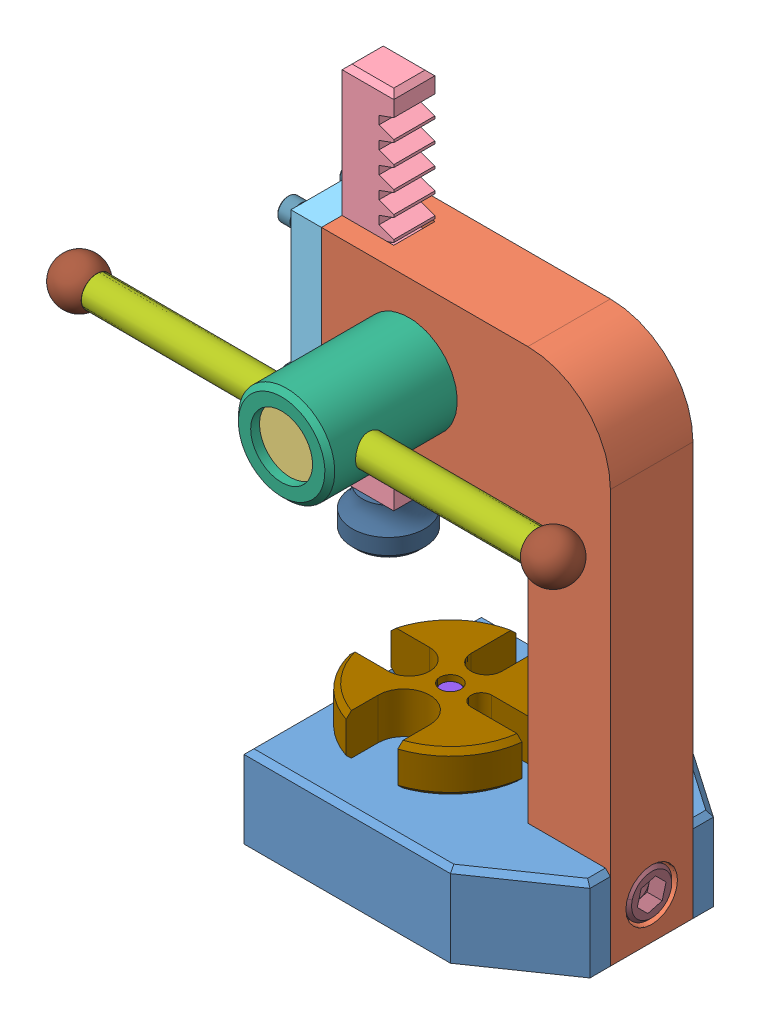
SolidWorks assembly Arbor_Press, configuration Default. Lengths in mm.
Overall size (160.09 192.74 88.38).
18 component instances, 14 part files, 29 mates.
Components (placement in the parent):
- Base-2: Base [Default] at origin size (88.9 25.4 73.03)
- Column Detail-1: Column Detail [Default] at (88.9 -12.7 0) size (88.9 152.4 25.4)
- Gear-1: Gear [Default] at (26.924 114.3 49.1998) x (0 0 -1) z (0.999994 -0.00338 0) size (61.9 29.01 29.01)
- Rack Gear-1: Rack Gear [Default] at (7.9375 68.9149 0) x (0 1 0) z (0 0 -1) size (111.12 15.88 12.65)
- Cover Plate-1: Cover Plate [Default] at (-9.398 114.3 0) x (0 0 1) z (1 0 0) size (25.4 50.8 9.4)
- Sleeve-1: Sleeve [Default] at (26.924 114.3 51.8668) x (0 0 -1) z (0.999994 -0.00338 0) size (42.62 29.64 29.64)
- Handle-1: Handle [Default] at (24.8888 114.3069 39.1668) x (0.999994 -0.00338 0) z (0.001333 0.394498 0.918896) size (152.4 9.45 9.45)
- Table Pin-1: Table Pin [Default] at (26.9748 -1.5748 0) x (-0.301577 0 0.953442) z (0 1 0) size (6.48 6.48 25.4)
- Table-1: Table [Default] at (26.9748 12.7 0) size (49.79 12.7 49.08)
- Rack Pad-1: Rack Pad [Default] at (7.9375 56.2149 0) size (22.24 26.97 22.24)
- Ball End-1: Ball End [Default] at (-47.9909 114.5532 39.1668) x (0.999994 -0.00338 0) z (0 0 1) size (12.45 14.27 14.27)
- Ball End-2: Ball End [Default] at (97.7685 114.0606 39.1668) x (-0.999994 0.00338 0) z (-0.002583 -0.764273 0.644888) size (12.45 14.27 14.27)
- Screw-1: Screw [Default] at (26.924 114.3 -3.2004) x (0.149888 -0.988703 0) z (0.988703 0.149888 0) size (19.05 14.74 19.05)
- _375-16x1_25x1_25-c_shcsa-1: _375-16x1_25x1_25-c_shcsa [Default] at (88.9 0 0) x (-1 0 0) z (0 0.259964 0.965618) size (41.27 14.29 14.29)
- 8-32 Socket Head Cap Screw_AI-2: 8-32 Socket Head Cap Screw_AI [PreviewCfg] at (-13.5636 136.525 -9.525) size (23.22 6.86 6.86)
- 8-32 Socket Head Cap Screw_AI-5: 8-32 Socket Head Cap Screw_AI [PreviewCfg] at (-13.5636 136.525 9.525) size (23.22 6.86 6.86)
- 8-32 Socket Head Cap Screw_AI-6: 8-32 Socket Head Cap Screw_AI [PreviewCfg] at (-13.5636 92.075 -9.525) size (23.22 6.86 6.86)
- 8-32 Socket Head Cap Screw_AI-7: 8-32 Socket Head Cap Screw_AI [PreviewCfg] at (-13.5636 92.075 9.525) size (23.22 6.86 6.86)
Mates (geometry in assembly coordinates):
- Concentric1: concentric: cylinder of Base-2 through (63.5 0 0) axis (1 0 0) radius 3.9688; cylinder of Column Detail-1 through (88.9 0 0) axis (1 0 0) radius 5.0419
- Coincident1: coincident: plane of Base-2 through (63.5 -12.7 -12.7) normal (1 0 0); plane of Column Detail-1 through (63.5 79.248 12.7) normal (-1 0 0)
- Parallel1: parallel: plane of Base-2 through (0 12.7 36.5125) normal (0 0 1); plane of Column Detail-1 through (63.5 114.3 12.7) normal (0 0 1)
- Concentric3: concentric: cylinder of Column Detail-1 through (26.924 114.3 12.7) axis (0 0 1) radius 6.35; cylinder of Gear-1 through (26.924 114.3 49.1998) axis (0 0 -1) radius 6.3348
- Coincident3: coincident: plane of Column Detail-1 through (63.5 114.3 -12.7) normal (0 0 -1); plane of Gear-1 through (26.9454 120.6347 -12.7) normal (0 0 -1)
- Width1: width: plane of Column Detail-1 through (15.9004 -12.7 -6.35) normal (0 0 1); plane of Column Detail-1 through (15.9004 -12.7 6.35) normal (0 0 -1); plane of Rack Gear-1 through (15.875 180.0399 -6.3246) normal (0 0 -1); plane of Rack Gear-1 through (15.875 180.0399 6.3246) normal (0 0 1)
- Coincident5: coincident: plane of Column Detail-1 through (0 139.7 12.7) normal (-1 0 0); plane of Rack Gear-1 through (0 180.0399 -6.3246) normal (-1 0 0)
- Concentric5: concentric: cylinder of Column Detail-1 through (0 136.525 -9.525) axis (-1 0 0) radius 1.7272; cylinder of Cover Plate-1 through (0 136.525 -9.525) axis (1 0 0) radius 2.2479
- Concentric6: concentric: cylinder of Column Detail-1 through (0 92.075 -9.525) axis (-1 0 0) radius 1.7272; cylinder of Cover Plate-1 through (0 92.075 -9.525) axis (1 0 0) radius 2.2479
- Coincident6: coincident: plane of Column Detail-1 through (0 139.7 12.7) normal (-1 0 0); plane of Cover Plate-1 through (0 114.3 0) normal (1 0 0)
- Concentric7: concentric: cylinder of Gear-1 through (26.924 114.3 49.1998) axis (0 0 -1) radius 9.4932; cylinder of Sleeve-1 through (26.924 114.3 9.2456) axis (0 0 -1) radius 9.525
- Concentric8: concentric: cylinder of Gear-1 through (36.4172 114.2679 39.1668) axis (0.999994 -0.00338 0) radius 4.7625; cylinder of Sleeve-1 through (41.7448 114.2499 39.1668) axis (0.999994 -0.00338 0) radius 4.7625
- Concentric9: concentric: cylinder of Gear-1 through (36.4172 114.2679 39.1668) axis (0.999994 -0.00338 0) radius 4.7625; cylinder of Handle-1 through (-51.3108 114.5644 39.1668) axis (-0.999994 0.00338 0) radius 4.7244
- Concentric10: concentric: cylinder of Base-2 through (26.9748 12.7 0) axis (0 1 0) radius 3.2385; cylinder of Table Pin-1 through (26.9748 23.8252 0) axis (0 -1 0) radius 3.2385
- Coincident7: coincident: plane of Base-2 through (26.9748 -1.5748 0) normal (0 1 0); plane of Table Pin-1 through (26.9748 -1.5748 0) normal (0 -1 0)
- Concentric11: concentric: cylinder of Table Pin-1 through (26.9748 23.8252 0) axis (0 -1 0) radius 3.2385; cylinder of Table-1 through (26.9748 25.4 0) axis (0 1 0) radius 3.2385
- Coincident8: coincident: plane of Base-2 through (0 12.7 0) normal (0 1 0); plane of Table-1 through (26.9748 12.7 0) normal (0 -1 0)
- Concentric12: concentric: cylinder of Rack Gear-1 through (7.9375 68.9149 0) axis (0 -1 0) radius 3.175; cylinder of Rack Pad-1 through (7.9375 56.2149 0) axis (0 1 0) radius 3.1686
- Coincident9: coincident: plane of Rack Gear-1 through (7.9375 68.9149 0) normal (0 -1 0); plane of Rack Pad-1 through (15.875 68.9149 0) normal (0 1 0)
- Concentric13: concentric: cylinder of Handle-1 through (-51.3108 114.5644 39.1668) axis (-0.999994 0.00338 0) radius 3.175; cylinder of Ball End-1 through (-42.6748 114.5352 39.1668) axis (0.999994 -0.00338 0) radius 2.5527
- Coincident10: coincident: plane of Handle-1 through (-42.665 117.4527 37.9143) normal (-0.999994 0.00338 0); plane of Ball End-1 through (-42.6748 114.5352 39.1668) normal (0.999994 -0.00338 0)
- Concentric14: concentric: cylinder of Handle-1 through (-51.3108 114.5644 39.1668) axis (-0.999994 0.00338 0) radius 3.175; cylinder of Ball End-2 through (92.4524 114.0785 39.1668) axis (-0.999994 0.00338 0) radius 2.5527
- Coincident11: coincident: plane of Handle-1 through (92.4623 116.996 37.9143) normal (0.999994 -0.00338 0); plane of Ball End-2 through (92.4524 114.0785 39.1668) normal (-0.999994 0.00338 0)
- Concentric15: concentric: cylinder of Gear-1 through (26.924 114.3 -12.7) axis (0 0 -1) radius 2.5527; cylinder of Screw-1 through (26.924 114.3 -3.2004) axis (0 0 1) radius 3.175
- Coincident12: coincident: plane of Gear-1 through (26.9454 120.6347 -12.7) normal (0 0 -1); plane of Screw-1 through (23.7849 113.8241 -12.7) normal (0 0 1)
- Concentric16: concentric: cylinder of Base-2 through (63.5 0 0) axis (1 0 0) radius 3.9688; cylinder of _375-16x1_25x1_25-c_shcsa-1 through (120.65 0 0) axis (-1 0 0) radius 4.7625
- Coincident13: coincident: plane of Column Detail-1 through (79.375 5.334 0) normal (1 0 0); plane of _375-16x1_25x1_25-c_shcsa-1 through (79.375 -6.8981 1.8571) normal (-1 0 0)
- Concentric18: concentric: cylinder of Cover Plate-1 through (0 136.525 -9.525) axis (1 0 0) radius 2.2479; cylinder of 8-32 Socket Head Cap Screw_AI-2 through (-45.3136 136.525 -9.525) axis (-1 0 0) radius 2.0828
- Coincident14: coincident: plane of Cover Plate-1 through (-9.398 114.3 0) normal (-1 0 0); plane of 8-32 Socket Head Cap Screw_AI-2 through (-9.398 139.954 -9.525) normal (1 0 0)
